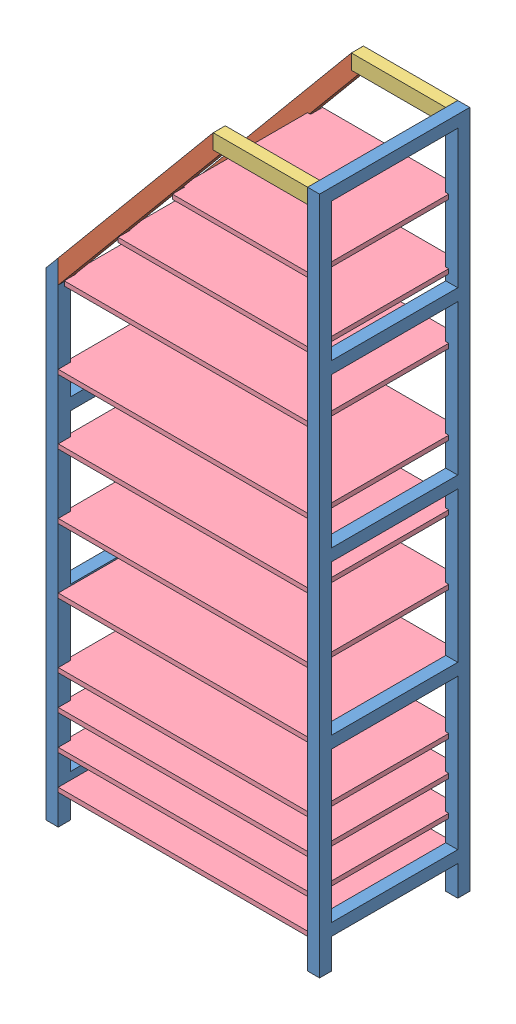
SolidWorks assembly Arbeitsregal, configuration Standard. Lengths in mm.
Overall size (910 2260 500).
17 component instances, 4 part files, 51 mates.
Components (placement in the parent):
- Seite-50-226-1: Seite-50-226 [Standard] at (-40 1130 250) size (40 2260 500)
- Seite-50-226-2: Seite-50-226 [Cut] at (-910 1130 250) size (40 1641 500)
- Schrägbalken-1: Schrägbalken [Standard] at (-870 1562.9047 460) size (539.33 697.1 40)
- Schrägbalken-2: Schrägbalken [Standard] at (-870 1562.9047 0) size (539.33 697.1 40)
- Querbalken-1: Querbalken [Standard] at (-323.1179 2235 460) size (314 50 40)
- Querbalken-2: Querbalken [Standard] at (-323.1179 2235 0) size (314 50 40)
- Boden-50-83-1: Boden-50-83 [Standard] at (-455 100 250) size (850 15 500)
- Boden-50-83-2: Boden-50-83 [Standard] at (-455 215 250) size (850 15 500)
- Boden-50-83-3: Boden-50-83 [Standard] at (-455 330 250) size (850 15 500)
- Boden-50-83-4: Boden-50-83 [Standard] at (-455 445 250) size (850 15 500)
- Boden-50-83-5: Boden-50-83 [Standard] at (-455 660 250) size (850 15 500)
- Boden-50-83-6: Boden-50-83 [Standard] at (-455 875 250) size (850 15 500)
- Boden-50-83-7: Boden-50-83 [Standard] at (-455 1090 250) size (850 15 500)
- Boden-50-83-8: Boden-50-83 [Standard] at (-455 1305 250) size (850 15 500)
- Boden-50-83-9: Boden-50-83 [Cut1] at (-455 1570 250) size (830 15 500)
- Boden-50-83-10: Boden-50-83 [Cut2] at (-455 1785 250) size (651 15 500)
- Boden-50-83-11: Boden-50-83 [Cut3] at (-455 2000 250) size (470 15 500)
Mates (geometry in assembly coordinates):
- Deckungsgleich1: coincident aligned: plane of Seite-50-226-1 through (0 2260 500) normal (0 0 1); plane of Boden-50-83-1 through (-870 115 500) normal (0 0 1)
- Deckungsgleich2: coincident aligned: plane of Seite-50-226-1 through (0 2260 500) normal (0 0 1); plane of Boden-50-83-2 through (-870 230 500) normal (0 0 1)
- Deckungsgleich3: coincident aligned: plane of Seite-50-226-1 through (0 2260 500) normal (0 0 1); plane of Boden-50-83-3 through (-870 345 500) normal (0 0 1)
- Deckungsgleich4: coincident aligned: plane of Seite-50-226-1 through (0 2260 500) normal (0 0 1); plane of Boden-50-83-4 through (-870 460 500) normal (0 0 1)
- Deckungsgleich5: coincident aligned: plane of Seite-50-226-1 through (0 2260 500) normal (0 0 1); plane of Boden-50-83-5 through (-870 675 500) normal (0 0 1)
- Deckungsgleich6: coincident aligned: plane of Seite-50-226-1 through (0 2260 500) normal (0 0 1); plane of Boden-50-83-6 through (-870 890 500) normal (0 0 1)
- Deckungsgleich7: coincident aligned: plane of Seite-50-226-1 through (0 2260 500) normal (0 0 1); plane of Boden-50-83-7 through (-870 1105 500) normal (0 0 1)
- Deckungsgleich10: coincident anti-aligned: plane of Seite-50-226-1 through (-40 1130 250) normal (-1 0 0); plane of Boden-50-83-1 through (-40 115 500) normal (1 0 0)
- Deckungsgleich11: coincident anti-aligned: plane of Seite-50-226-1 through (-40 1130 250) normal (-1 0 0); plane of Boden-50-83-2 through (-40 230 500) normal (1 0 0)
- Deckungsgleich12: coincident anti-aligned: plane of Seite-50-226-1 through (-40 1130 250) normal (-1 0 0); plane of Boden-50-83-3 through (-40 345 500) normal (1 0 0)
- Deckungsgleich13: coincident anti-aligned: plane of Seite-50-226-1 through (-40 1130 250) normal (-1 0 0); plane of Boden-50-83-4 through (-40 460 500) normal (1 0 0)
- Deckungsgleich14: coincident anti-aligned: plane of Seite-50-226-1 through (-40 1130 250) normal (-1 0 0); plane of Boden-50-83-5 through (-40 675 500) normal (1 0 0)
- Deckungsgleich15: coincident anti-aligned: plane of Seite-50-226-1 through (-40 1130 250) normal (-1 0 0); plane of Boden-50-83-6 through (-40 890 500) normal (1 0 0)
- Deckungsgleich16: coincident anti-aligned: plane of Seite-50-226-1 through (-40 1130 250) normal (-1 0 0); plane of Boden-50-83-7 through (-40 1105 500) normal (1 0 0)
- Abstand1: distance = 100 mm aligned: plane of Boden-50-83-1 through (-455 100 250) normal (0 -1 0); plane of Seite-50-226-1 through (0 0 500) normal (0 -1 0)
- Abstand2: distance = 100 mm anti-aligned: plane of Boden-50-83-2 through (-455 215 250) normal (0 -1 0); plane of Boden-50-83-1 through (-455 115 250) normal (0 1 0)
- Abstand3: distance = 100 mm anti-aligned: plane of Boden-50-83-3 through (-455 330 250) normal (0 -1 0); plane of Boden-50-83-2 through (-455 230 250) normal (0 1 0)
- Abstand4: distance = 100 mm anti-aligned: plane of Boden-50-83-3 through (-455 345 250) normal (0 1 0); plane of Boden-50-83-4 through (-455 445 250) normal (0 -1 0)
- Abstand5: distance = 200 mm anti-aligned: plane of Boden-50-83-4 through (-455 460 250) normal (0 1 0); plane of Boden-50-83-5 through (-455 660 250) normal (0 -1 0)
- Abstand6: distance = 200 mm anti-aligned: plane of Boden-50-83-6 through (-455 875 250) normal (0 -1 0); plane of Boden-50-83-5 through (-455 675 250) normal (0 1 0)
- Abstand7: distance = 200 mm anti-aligned: plane of Boden-50-83-6 through (-455 890 250) normal (0 1 0); plane of Boden-50-83-7 through (-455 1090 250) normal (0 -1 0)
- Deckungsgleich47: coincident aligned: plane of Seite-50-226-1 through (0 2260 500) normal (0 0 1); plane of Querbalken-1 through (-323.1179 2235 500) normal (0 0 1)
- Deckungsgleich48: coincident anti-aligned: plane of Seite-50-226-1 through (-40 1130 250) normal (-1 0 0); plane of Querbalken-1 through (-40 2210 500) normal (1 0 0)
- Deckungsgleich49: coincident anti-aligned: plane of Schrägbalken-1 through (-330.6692 2210 500) normal (0 1 0); plane of Querbalken-1 through (-354 2210 500) normal (0 -1 0)
- Deckungsgleich62: coincident aligned: plane of Seite-50-226-1 through (0 2260 0) normal (0 0 -1); plane of Querbalken-2 through (-323.1179 2235 0) normal (0 0 -1)
- Deckungsgleich63: coincident aligned: plane of Querbalken-2 through (-323.1179 2235 0) normal (0 0 -1); plane of Schrägbalken-2 through (-870 1562.9047 0) normal (0 0 -1)
- Deckungsgleich65: coincident anti-aligned: plane of Querbalken-2 through (-354 2210 40) normal (0 -1 0); plane of Schrägbalken-2 through (-330.6692 2210 40) normal (0 1 0)
- Deckungsgleich67: coincident anti-aligned: plane of Seite-50-226-1 through (-40 1130 250) normal (-1 0 0); plane of Querbalken-2 through (-40 2210 40) normal (1 0 0)
- Deckungsgleich69: coincident aligned: plane of Seite-50-226-1 through (0 1130 250) normal (1 0 0); plane of assembly through (0 0 0) normal (1 0 0)
- Deckungsgleich70: coincident anti-aligned: plane of Seite-50-226-1 through (0 0 40) normal (0 -1 0); plane of assembly through (0 0 0) normal (0 1 0)
- Deckungsgleich71: coincident anti-aligned: plane of Seite-50-226-1 through (0 2260 0) normal (0 0 -1); plane of assembly through (0 0 0) normal (0 0 1)
- Deckungsgleich72: coincident aligned: plane of Boden-50-83-7 through (-870 1105 500) normal (0 0 1); plane of Boden-50-83-8 through (-870 1320 500) normal (0 0 1)
- Deckungsgleich73: coincident aligned: plane of Boden-50-83-7 through (-30 1105 40) normal (1 0 0); plane of Boden-50-83-8 through (-30 1320 40) normal (1 0 0)
- Abstand18: distance = 200 mm anti-aligned: plane of Boden-50-83-7 through (-455 1105 250) normal (0 1 0); plane of Boden-50-83-8 through (-455 1305 250) normal (0 -1 0)
- Deckungsgleich74: coincident aligned: plane of Seite-50-226-1 through (0 2260 500) normal (0 0 1); plane of Seite-50-226-2 through (-870 2260 500) normal (0 0 1)
- Deckungsgleich75: coincident aligned: plane of Seite-50-226-1 through (0 0 500) normal (0 -1 0); plane of Seite-50-226-2 through (-870 0 500) normal (0 -1 0)
- Deckungsgleich76: coincident anti-aligned: plane of Boden-50-83-1 through (-870 115 460) normal (-1 0 0); plane of Seite-50-226-2 through (-870 1130 250) normal (1 0 0)
- Deckungsgleich77: coincident anti-aligned: plane of Seite-50-226-2 through (-870 1130 250) normal (1 0 0); plane of Schrägbalken-1 through (-870 1641 500) normal (-1 0 0)
- Deckungsgleich78: coincident aligned: plane of Seite-50-226-2 through (-870 1641 -100) normal (-0.768172 0.640244 0); plane of Schrägbalken-1 through (-354.0856 2260 500) normal (-0.768172 0.640244 0)
- Deckungsgleich79: coincident aligned: plane of Seite-50-226-2 through (-870 2260 500) normal (0 0 1); plane of Schrägbalken-1 through (-870 1562.9047 500) normal (0 0 1)
- Deckungsgleich80: coincident aligned: plane of Seite-50-226-2 through (-870 1641 -100) normal (-0.768172 0.640244 0); plane of Schrägbalken-2 through (-354.0856 2260 40) normal (-0.768172 0.640244 0)
- Deckungsgleich81: coincident anti-aligned: plane of Seite-50-226-2 through (-870 1130 250) normal (1 0 0); plane of Schrägbalken-2 through (-870 1641 40) normal (-1 0 0)
- Abstand19: distance = 250 mm anti-aligned: plane of Boden-50-83-9 through (-455 1570 250) normal (0 -1 0); plane of Boden-50-83-8 through (-455 1320 250) normal (0 1 0)
- Deckungsgleich84: coincident aligned: plane of Boden-50-83-8 through (-30 1320 40) normal (1 0 0); plane of Boden-50-83-9 through (-30 1585 40) normal (1 0 0)
- Deckungsgleich85: coincident aligned: plane of Boden-50-83-8 through (-870 1320 500) normal (0 0 1); plane of Boden-50-83-9 through (-870 1585 500) normal (0 0 1)
- Abstand20: distance = 200 mm anti-aligned: plane of Boden-50-83-9 through (-455 1585 250) normal (0 1 0); plane of Boden-50-83-10 through (-455 1785 250) normal (0 -1 0)
- Deckungsgleich87: coincident aligned: plane of Boden-50-83-9 through (-870 1585 500) normal (0 0 1); plane of Boden-50-83-10 through (-870 1800 500) normal (0 0 1)
- Deckungsgleich88: coincident aligned: plane of Boden-50-83-9 through (-30 1585 40) normal (1 0 0); plane of Boden-50-83-10 through (-30 1800 40) normal (1 0 0)
- Abstand21: distance = 200 mm anti-aligned: plane of Boden-50-83-11 through (-455 2000 250) normal (0 -1 0); plane of Boden-50-83-10 through (-455 1800 250) normal (0 1 0)
- Deckungsgleich90: coincident aligned: plane of Boden-50-83-10 through (-30 1800 40) normal (1 0 0); plane of Boden-50-83-11 through (-30 2015 40) normal (1 0 0)
- Deckungsgleich91: coincident aligned: plane of Boden-50-83-10 through (-870 1800 500) normal (0 0 1); plane of Boden-50-83-11 through (-870 2015 500) normal (0 0 1)
